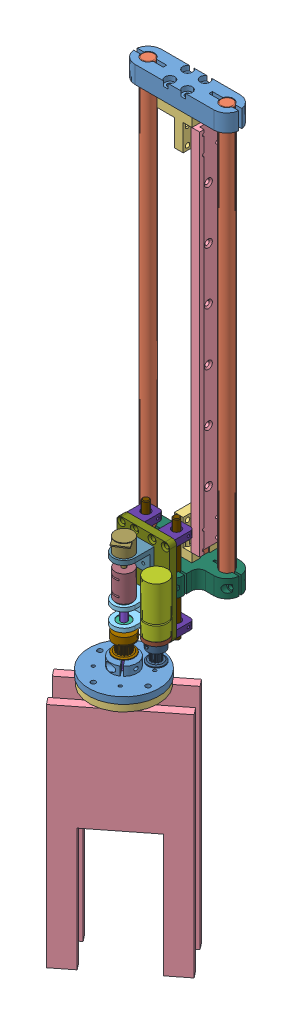
SolidWorks assembly wrist-vert-piece, configuration Default. Lengths in mm.
Overall size (90.81 526.18 99.39).
33 component instances, 23 part files, 26 mates.
Components (placement in the parent):
- w01-shaft-hold-tio-1: w01-shaft-hold-tio [Default] at (-52.8069 -5.7767 27.476) size (77.36 12.7 20.32)
- xx-p5sHAFT-6253k32-mcm-1: xx-p5sHAFT-6253k32-mcm [Default] at (-81.3819 -145.4767 27.476) size (9.53 304.8 9.53)
- xx-p5sHAFT-6253k32-mcm-3: xx-p5sHAFT-6253k32-mcm [Default] at (-24.2319 -145.4767 27.476) x (0 0 -1) z (1 0 0) size (9.53 304.8 9.53)
- xx--fake-hand-asm-1: xx--fake-hand-asm [Default] at (-52.8069 -429.0793 73.5135) x (0.786463 0 -0.617638) z (-0.617638 0 -0.786463) size (76.2 175.18 50)
  - wrist-1: wrist [Default] at origin size (50 85 50)
  - xx-fake-hand-1: xx-fake-hand [Default] at (0 1.28 15.85) x (1 0 0) z (0 0 -1) size (76.2 165.1 6.35)
  - xx-fake-hand-2: xx-fake-hand [Default] at (0 1.28 -9.5) x (1 0 0) z (0 0 -1) size (76.2 165.1 6.35)
- wrist-yaw-joint-1: wrist-yaw-joint [Default] at (-52.8069 -303.5917 59.5435) x (1 0 0) z (0 -1 0) size (76.14 66.56 87.16)
  - n05-headyoke-1: n05-headyoke [Default] at origin size (15.88 21.91 15.88)
  - p1875bearing-57155K319-MCM-1: p1875bearing-57155K319-MCM [Default] at (0 13.97 5.5499) x (0 0 -1) z (0 -1 0) size (3.17 11.18 11.18)
  - p1875bearing-57155K319-MCM-2: p1875bearing-57155K319-MCM [Default] at (0 13.97 -5.5499) x (0 0 1) z (0 -1 0) size (3.17 11.18 11.18)
  - MAXON-AMAX16-110049-110323-1: MAXON-AMAX16-110049-110323 [Default] at (17.4625 8.128 -28.5125) x (0 0 -1) z (1 0 0) size (48.2 16 16)
  - n06-p1875shaft-1: n06-p1875shaft [Default] at (0 13.97 -15.0749) size (4.76 4.76 50.8)
  - a_6d16-016df2506-p1875bore-16teeth-1: a_6d16-016df2506-p1875bore-16teeth [Default] at (0 13.97 17.218) x (0.167713 -0.985836 0) z (0 0 -1) size (14.73 14.73 14.29)
  - a_6d16m012df6003-3mm-bored-to-4mm-1: a_6d16m012df6003-3mm-bored-to-4mm [Default] at (17.4625 8.128 17.2524) x (-0.948708 0.316155 0) z (0 0 -1) size (12.2 12.2 14.3)
  - a_6n16-015df1206-2: a_6n16-015df1206 [Default] at (-14.2838 6.954 15.9813) x (0.986257 0.164531 -0.015045) z (-0.021924 0.040076 -0.998956) size (14.1 14.1 11.13) (hidden)
  - n09-motor-holder-1: n09-motor-holder [Default] at (17.4625 8.128 7.9375) size (33.53 16.26 2.79)
  - POT-eti-sys-EUP125-1: POT-eti-sys-EUP125 [Default] at (0 13.97 -47.4345) x (0 0 -1) z (0.836462 -0.548026 0) size (30.58 15.39 13)
  - 000_helical-coupling-6208K53-MCM-1: 000_helical-coupling-6208K53-MCM [Default] at (0 13.97 -18.3769) size (12.7 12.7 19.05)
  - n10-potholder-1: n10-potholder [Default] at (0 0 -29.5148) size (15.88 21.91 15.88)
  - w04-shaft-hold-bottom-2: w04-shaft-hold-bottom [Default] at (0 -32.0675 -5.715) x (1 0 0) z (0 1 0) size (76.14 12.7 34.92)
  - w06-plate-1: w06-plate [Default] at (0 0 -12.7) x (1 0 0) z (0 -1 0) size (38.1 63.5 5.08)
  - w07-clamp-1: w07-clamp [Default] at (11.1125 -13.0175 -43.815) size (12.7 14.29 5.08)
  - w07-clamp-2: w07-clamp [Default] at (11.1125 -13.0175 13.335) size (12.7 14.29 5.08)
  - w07-clamp-3: w07-clamp [Default] at (-11.1125 -13.0175 -43.815) size (12.7 14.29 5.08)
  - w07-clamp-4: w07-clamp [Default] at (-11.1125 -13.0175 13.335) size (12.7 14.29 5.08)
  - w08-p1875shaft-1: w08-p1875shaft [Default] at (-11.1125 -13.0175 -51.435) size (4.76 4.76 76.2)
  - w08-p1875shaft-2: w08-p1875shaft [Default] at (11.1125 -13.0175 -51.435) size (4.76 4.76 76.2)
- w05-hand-mount-1: w05-hand-mount [Default] at (-52.8069 -344.0793 73.5135) x (0.786463 0 -0.617638) z (0.617638 0 0.786463) size (50.8 12.7 50.8)
- 000_gearrack_mcm-6295K12-1: 000_gearrack_mcm-6295K12 [Default] at (-40.8689 -151.8267 27.476) x (0 -1 0) z (0 0 -1) size (266.7 6.35 6.35)
- w10-el-2-el-1: w10-el-2-el [Default] at (-40.1069 -5.7767 27.476) x (1 0 0) z (0 0 -1) size (25.4 25.4 19.05)
- w10-el-2-el-2: w10-el-2-el [Default] at (-40.1069 -285.1767 27.476) size (25.4 25.4 19.05)
- w09-al-el-1: w09-al-el [Default] at (-40.8689 -145.4767 37.001) x (0 0 1) z (-1 0 0) size (19.05 266.7 6.35)
Mates (geometry in assembly coordinates):
- Coincident1: coincident aligned: plane of w01-shaft-hold-tio-1 through (-81.3819 6.9233 27.476) normal (0 1 0); plane of xx-p5sHAFT-6253k32-mcm-1 through (-81.3819 6.9233 27.476) normal (0 1 0)
- Concentric1: concentric aligned: cylinder of w01-shaft-hold-tio-1; cylinder of xx-p5sHAFT-6253k32-mcm-1
- Concentric2: concentric aligned: cylinder of w01-shaft-hold-tio-1; cylinder of xx-p5sHAFT-6253k32-mcm-3
- Coincident2: coincident aligned: plane of w01-shaft-hold-tio-1 through (-81.3819 6.9233 27.476) normal (0 1 0); circle of xx-p5sHAFT-6253k32-mcm-3 centre (-24.2319 6.9233 27.476) axis (0 1 0)
- Parallel1: parallel: line of w01-shaft-hold-tio-1; plane of xx-p5sHAFT-6253k32-mcm-1 through (-81.3819 -145.4767 27.476) normal (0 0 1)
- Parallel2: parallel anti-aligned: plane of w01-shaft-hold-tio-1 through (-24.2319 6.9233 37.636) normal (0 0 1); plane of xx-p5sHAFT-6253k32-mcm-3 through (-24.2319 -145.4767 27.476) normal (0 0 -1)
- Concentric3: concentric anti-aligned: cylinder of xx--fake-hand-asm-1/wrist-1; cylinder of wrist-yaw-joint-1/n06-p1875shaft-1
- Concentric4: concentric anti-aligned: cylinder of xx--fake-hand-asm-1/wrist-1; cylinder of w05-hand-mount-1
- Concentric5: concentric anti-aligned: cylinder of xx--fake-hand-asm-1/wrist-1; cylinder of w05-hand-mount-1
- Coincident3: coincident anti-aligned: plane of xx--fake-hand-asm-1/wrist-1 through (-52.8069 -344.0793 73.5135) normal (0 1 0); plane of w05-hand-mount-1 through (-52.8069 -344.0793 73.5135) normal (0 -1 0)
- Coincident4: coincident anti-aligned: plane of wrist-yaw-joint-1/n06-p1875shaft-1 through (-52.8069 -339.3168 73.5135) normal (0 -1 0); plane of w05-hand-mount-1 through (-52.8069 -339.3168 73.5135) normal (0 1 0)
- Coincident5: coincident aligned: unknown of wrist-yaw-joint-1/w04-shaft-hold-bottom-2
- Concentric6: concentric aligned: unknown of wrist-yaw-joint-1/w04-shaft-hold-bottom-2
- Concentric7: concentric aligned: unknown of wrist-yaw-joint-1/w04-shaft-hold-bottom-2
- Distance1: distance = 0 mm anti-aligned: plane of w01-shaft-hold-tio-1 through (-52.8069 -5.7767 27.476) normal (0 0 1); plane of 000_gearrack_mcm-6295K12-1 through (-40.8689 -151.8267 27.476) normal (0 0 -1)
- Distance3: distance = 12.7 mm anti-aligned: plane of w01-shaft-hold-tio-1 through (-81.3819 -5.7767 27.476) normal (0 -1 0); plane of 000_gearrack_mcm-6295K12-1 through (-40.8689 -18.4767 24.301) normal (0 1 0)
- Concentric8: concentric aligned: cylinder of w01-shaft-hold-tio-1; cylinder of w10-el-2-el-1
- Concentric9: concentric aligned: cylinder of w01-shaft-hold-tio-1; cylinder of w10-el-2-el-1
- Coincident6: coincident anti-aligned: plane of w01-shaft-hold-tio-1 through (-81.3819 -5.7767 27.476) normal (0 -1 0); plane of w10-el-2-el-1 through (-40.1069 -5.7767 17.951) normal (0 1 0)
- Coincident7: coincident anti-aligned: plane of wrist-yaw-joint-1/w04-shaft-hold-bottom-2 through (-81.3819 -285.1767 27.476) normal (0 1 0); plane of w10-el-2-el-2 through (-40.1069 -285.1767 37.001) normal (0 -1 0)
- Concentric10: concentric aligned: cylinder of wrist-yaw-joint-1/w04-shaft-hold-bottom-2; cylinder of w10-el-2-el-2
- Coincident8: coincident aligned: plane of w10-el-2-el-1 through (-40.1069 -31.1767 37.001) normal (0 0 1); plane of w10-el-2-el-2 through (-40.1069 -259.7767 37.001) normal (0 0 1)
- Coincident9: coincident anti-aligned: plane of w09-al-el-1 through (-40.8689 -12.1267 17.951) normal (-1 0 0); plane of 000_gearrack_mcm-6295K12-1 through (-40.8689 -285.1767 24.301) normal (1 0 0)
- Concentric11: concentric aligned: cylinder of w10-el-2-el-1; cylinder of w09-al-el-1
- Concentric12: concentric aligned: cylinder of w10-el-2-el-1; cylinder of w09-al-el-1
- Coincident10: coincident anti-aligned: plane of 000_gearrack_mcm-6295K12-1 through (-47.2189 -285.1767 24.301) normal (-1 0 0); plane of w10-el-2-el-1 through (-47.2189 -5.7767 30.778) normal (1 0 0)
